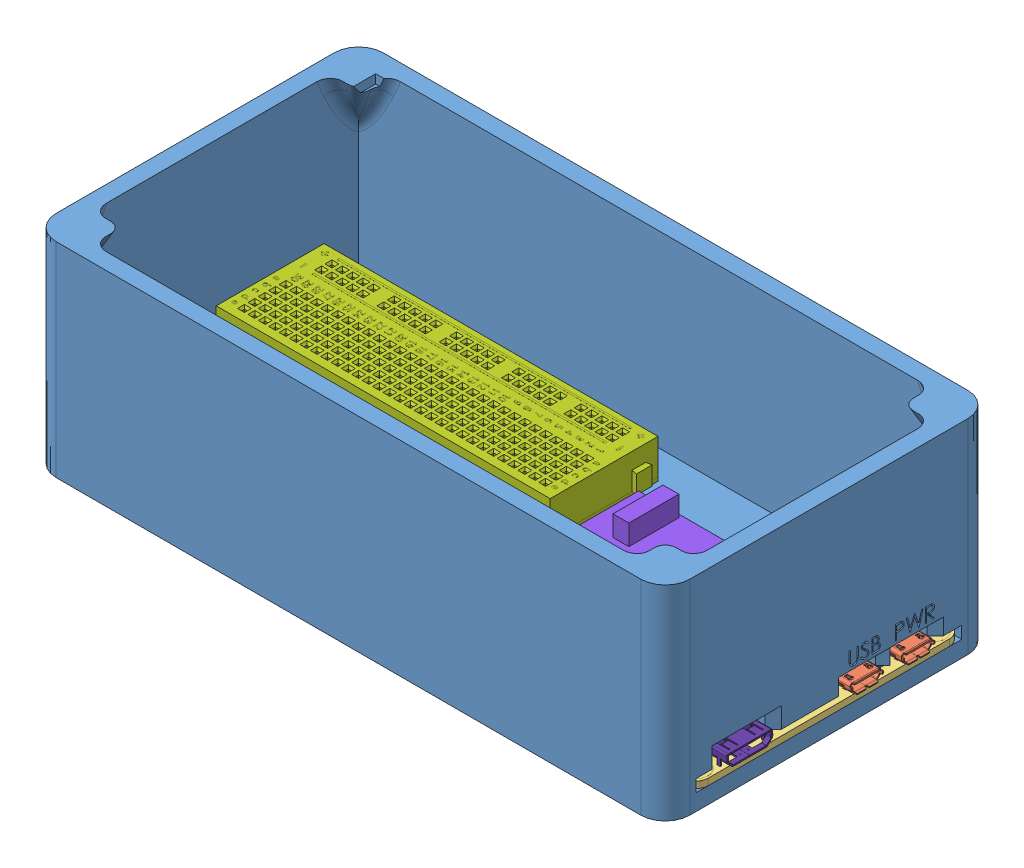
SolidWorks assembly pi, box, configuration Default. Lengths in mm.
Overall size (155.65 50 80).
137 component instances, 26 part files, 12 mates.
Components (placement in the parent):
- pi box-1: pi box [Default] at (-36.1116 -16.0772 12.9936) size (155 50 80)
- Raspberry PI Zero WH-2: Raspberry PI Zero WH [Default] at (41.3884 -12.0772 45.4936) x (0 0 -1) z (0 1 0) size (65 30.65 11.38)
  - micro_usb_connector v17.step-3: micro_usb_connector v17.step [Default] at (41.4 3 1.74) x (0 -1 0) z (0 0 1) size (5.84 7.77 3.4)
    - shield.step-1: shield.step [Default] at origin size (5.84 7.77 3.4)
    - socket_housing.step-1: socket_housing.step [Default] at origin size (4.25 6.85 2.15)
    - socket_plate.step-1: socket_plate.step [Default] at origin size (3.38 6.8 0.31)
    - terminal.step-1: terminal.step [Default] at origin size (3.22 0.35 1.72)
    - terminal.step-2: terminal.step [Default] at (0 -1.3 0) size (3.22 0.35 1.72)
    - terminal.step-3: terminal.step [Default] at (0 -0.65 0) size (3.22 0.35 1.72)
    - terminal.step-4: terminal.step [Default] at (0 0.65 0) size (3.22 0.35 1.72)
    - terminal.step-5: terminal.step [Default] at (0 1.3 0) size (3.22 0.35 1.72)
  - micro_usb_connector v17.step-4: micro_usb_connector v17.step [Default] at (54 3 1.74) x (0 -1 0) z (0 0 1) size (5.84 7.77 3.4)
    - shield.step-1: shield.step [Default] at origin size (5.84 7.77 3.4)
    - socket_housing.step-1: socket_housing.step [Default] at origin size (4.25 6.85 2.15)
    - socket_plate.step-1: socket_plate.step [Default] at origin size (3.38 6.8 0.31)
    - terminal.step-1: terminal.step [Default] at origin size (3.22 0.35 1.72)
    - terminal.step-2: terminal.step [Default] at (0 -1.3 0) size (3.22 0.35 1.72)
    - terminal.step-3: terminal.step [Default] at (0 -0.65 0) size (3.22 0.35 1.72)
    - terminal.step-4: terminal.step [Default] at (0 0.65 0) size (3.22 0.35 1.72)
    - terminal.step-5: terminal.step [Default] at (0 1.3 0) size (3.22 0.35 1.72)
  - Components.step-2: Components.step [Default] at origin size (59.43 22.49 1.8)
    - CAPC-0402-T0.55-BN.step-1: CAPC-0402-T0.55-BN.step [Default] at (33.3698 17.6201 1.6) size (1.05 0.55 0.55)
    - CAPC-0402-T0.55-BN.step-2: CAPC-0402-T0.55-BN.step [Default] at (33.3698 16.6201 1.6) size (1.05 0.55 0.55)
    - CAPC-0402-T0.55-BN.step-3: CAPC-0402-T0.55-BN.step [Default] at (33.3698 15.6201 1.6) size (1.05 0.55 0.55)
    - CAPC-0402-T0.55-BN.step-4: CAPC-0402-T0.55-BN.step [Default] at (33.3698 14.6201 1.6) size (1.05 0.55 0.55)
    - CAPC-0402-T0.55-BN.step-5: CAPC-0402-T0.55-BN.step [Default] at (33.3698 13.6201 1.6) size (1.05 0.55 0.55)
    - CAPC-0402-T0.55-BN.step-6: CAPC-0402-T0.55-BN.step [Default] at (33.3698 12.6201 1.6) size (1.05 0.55 0.55)
    - CAPC-0402-T0.55-BN.step-7: CAPC-0402-T0.55-BN.step [Default] at (33.3698 11.6201 1.6) size (1.05 0.55 0.55)
    - CAPC-0402-T0.55-BN.step-8: CAPC-0402-T0.55-BN.step [Default] at (35.2975 17.3433 1.6) x (0 -1 0) z (0 0 1) size (1.05 0.55 0.55)
    - CAPC-0402-T0.55-BN.step-9: CAPC-0402-T0.55-BN.step [Default] at (35.2975 15.5933 1.6) x (0 -1 0) z (0 0 1) size (1.05 0.55 0.55)
    - CAPC-0402-T0.55-BN.step-10: CAPC-0402-T0.55-BN.step [Default] at (20.7555 5.9273 1.6) x (0 -1 0) z (0 0 1) size (1.05 0.55 0.55)
    - CAPC-0402-T0.55-BN.step-11: CAPC-0402-T0.55-BN.step [Default] at (21.5605 5.9273 1.6) x (0 -1 0) z (0 0 1) size (1.05 0.55 0.55)
    - CAPC-0402-T0.55-BN.step-12: CAPC-0402-T0.55-BN.step [Default] at (22.3655 5.9273 1.6) x (0 -1 0) z (0 0 1) size (1.05 0.55 0.55)
    - CAPC-0402-T0.55-BN.step-13: CAPC-0402-T0.55-BN.step [Default] at (23.1705 5.9273 1.6) x (0 -1 0) z (0 0 1) size (1.05 0.55 0.55)
    - CAPC-0402-T0.55-BN.step-14: CAPC-0402-T0.55-BN.step [Default] at (23.9755 5.9273 1.6) x (0 -1 0) z (0 0 1) size (1.05 0.55 0.55)
    - CAPC-0402-T0.55-BN.step-15: CAPC-0402-T0.55-BN.step [Default] at (24.7805 5.9273 1.6) x (0 -1 0) z (0 0 1) size (1.05 0.55 0.55)
    - CAPC-0402-T0.55-BN.step-16: CAPC-0402-T0.55-BN.step [Default] at (25.5855 5.9273 1.6) x (0 -1 0) z (0 0 1) size (1.05 0.55 0.55)
    - CAPC-0402-T0.55-BN.step-17: CAPC-0402-T0.55-BN.step [Default] at (26.3905 5.9273 1.6) x (0 -1 0) z (0 0 1) size (1.05 0.55 0.55)
    - CAPC-0402-T0.55-BN.step-18: CAPC-0402-T0.55-BN.step [Default] at (27.1955 5.9273 1.6) x (0 -1 0) z (0 0 1) size (1.05 0.55 0.55)
    - CAPC-0402-T0.55-BN.step-19: CAPC-0402-T0.55-BN.step [Default] at (28.0005 5.9273 1.6) x (0 -1 0) z (0 0 1) size (1.05 0.55 0.55)
    - CAPC-0402-T0.55-BN.step-20: CAPC-0402-T0.55-BN.step [Default] at (34.1 10.6 1.6) size (1.05 0.55 0.55)
    - CAPC-0402-T0.55-BN.step-21: CAPC-0402-T0.55-BN.step [Default] at (34.1 9.79 1.6) size (1.05 0.55 0.55)
    - CAPC-0402-T0.55-BN.step-22: CAPC-0402-T0.55-BN.step [Default] at (34.1 8.98 1.6) size (1.05 0.55 0.55)
    - CAPC-0402-T0.55-BN.step-23: CAPC-0402-T0.55-BN.step [Default] at (34.1 8.17 1.6) size (1.05 0.55 0.55)
    - CAPC-0402-T0.55-BN.step-24: CAPC-0402-T0.55-BN.step [Default] at (34.1 7.36 1.6) size (1.05 0.55 0.55)
    - CAPC-0402-T0.55-BN.step-25: CAPC-0402-T0.55-BN.step [Default] at (17.4437 19.1633 1.6) size (1.05 0.55 0.55)
    - CAPC-0402-T0.55-BN.step-26: CAPC-0402-T0.55-BN.step [Default] at (17.4437 18.1633 1.6) size (1.05 0.55 0.55)
    - CAPC-0402-T0.55-BN.step-27: CAPC-0402-T0.55-BN.step [Default] at (17.4437 17.1633 1.6) size (1.05 0.55 0.55)
    - CAPC-0402-T0.55-BN.step-28: CAPC-0402-T0.55-BN.step [Default] at (17.4437 16.1633 1.6) size (1.05 0.55 0.55)
    - CAPC-0402-T0.55-BN.step-29: CAPC-0402-T0.55-BN.step [Default] at (17.4437 15.1633 1.6) size (1.05 0.55 0.55)
    - CAPC-0402-T0.55-BN.step-30: CAPC-0402-T0.55-BN.step [Default] at (17.9697 14.164 1.6) size (1.05 0.55 0.55)
    - CAPC-0402-T0.55-BN.step-31: CAPC-0402-T0.55-BN.step [Default] at (17.9697 13.344 1.6) size (1.05 0.55 0.55)
    - CAPC-0402-T0.55-BN.step-32: CAPC-0402-T0.55-BN.step [Default] at (31.3668 5.5372 1.6) size (1.05 0.55 0.55)
    - CAPC-0402-T0.55-BN.step-33: CAPC-0402-T0.55-BN.step [Default] at (36.2259 10.107 1.6) x (0 -1 0) z (0 0 1) size (1.05 0.55 0.55)
    - CAPC-0402-T0.55-BN.step-34: CAPC-0402-T0.55-BN.step [Default] at (30.8759 20.015 1.6) size (1.05 0.55 0.55)
    - CAPC-0402-T0.55-BN.step-35: CAPC-0402-T0.55-BN.step [Default] at (25.6574 20.7007 1.6) x (0 -1 0) z (0 0 1) size (1.05 0.55 0.55)
    - CAPC-0402-T0.55-BN.step-36: CAPC-0402-T0.55-BN.step [Default] at (24.6574 20.7007 1.6) x (0 -1 0) z (0 0 1) size (1.05 0.55 0.55)
    - CAPC-0402-T0.55-BN.step-37: CAPC-0402-T0.55-BN.step [Default] at (23.6574 20.7007 1.6) x (0 -1 0) z (0 0 1) size (1.05 0.55 0.55)
    - CAPC-0402-T0.55-BN.step-38: CAPC-0402-T0.55-BN.step [Default] at (20.2103 20.6923 1.6) x (0 -1 0) z (0 0 1) size (1.05 0.55 0.55)
    - CAPC-0402-T0.55-BN.step-39: CAPC-0402-T0.55-BN.step [Default] at (39.0204 12.9386 1.6) size (1.05 0.55 0.55)
    - CAPC-0402-T0.55-BN.step-40: CAPC-0402-T0.55-BN.step [Default] at (40.6631 15.6901 1.6) size (1.05 0.55 0.55)
    - CAPC-0402-T0.55-BN.step-41: CAPC-0402-T0.55-BN.step [Default] at (39.3678 16.5618 1.6) size (1.05 0.55 0.55)
    - CAPC-0402-T0.55-BN.step-42: CAPC-0402-T0.55-BN.step [Default] at (42.831 16.9675 1.6) x (0 -1 0) z (0 0 1) size (1.05 0.55 0.55)
    - CAPC-0402-T0.55-BN.step-43: CAPC-0402-T0.55-BN.step [Default] at (41.2678 16.5618 1.6) size (1.05 0.55 0.55)
    - CAPC-0402-T0.55-BN.step-44: CAPC-0402-T0.55-BN.step [Default] at (5.0529 7.1196 1.6) size (1.05 0.55 0.55)
    - CAPC-0402-T0.55-BN.step-45: CAPC-0402-T0.55-BN.step [Default] at (37.9324 22.363 1.6) size (1.05 0.55 0.55)
    - CAPC-0402-T0.55-BN.step-46: CAPC-0402-T0.55-BN.step [Default] at (52.706 14.1667 1.6) size (1.05 0.55 0.55)
    - CAPC-0603-T0.9-BN.step-1: CAPC-0603-T0.9-BN.step [Default] at (1.2622 8.8622 1.6) x (0 -1 0) z (0 0 1) size (1.7 0.9 0.9)
    - CAPC-0402-T0.55-BN.step-47: CAPC-0402-T0.55-BN.step [Default] at (19.3797 6.5002 1.6) size (1.05 0.55 0.55)
    - CAPC-0402-T0.55-BN.step-48: CAPC-0402-T0.55-BN.step [Default] at (19.3316 1.3043 1.6) size (1.05 0.55 0.55)
    - CAPC-0603-T0.9-BN.step-2: CAPC-0603-T0.9-BN.step [Default] at (33.8953 18.8389 1.6) size (1.7 0.9 0.9)
    - INDC-0603.step-1: INDC-0603.step [Default] at (39.8621 18.1224 1.6) size (1.75 0.95 0.95)
    - INDC-0603.step-2: INDC-0603.step [Default] at (39.1295 14.7453 1.6) x (0 -1 0) z (0 0 1) size (1.75 0.95 0.95)
    - INDC-0402.step-1: INDC-0402.step [Default] at (29.426 5.5149 1.6) size (1.05 0.55 0.55)
    - INDC-0402.step-2: INDC-0402.step [Default] at (41.7855 10.5602 1.6) size (1.05 0.55 0.55)
    - INDC-0402.step-3: INDC-0402.step [Default] at (41.7855 9.7502 1.6) size (1.05 0.55 0.55)
    - INDC-0402.step-4: INDC-0402.step [Default] at (46.2071 10.726 1.6) size (1.05 0.55 0.55)
    - INDC-0402.step-5: INDC-0402.step [Default] at (18.9188 8.3162 1.6) size (1.05 0.55 0.55)
    - INDC-0402.step-6: INDC-0402.step [Default] at (16.9188 8.3162 1.6) size (1.05 0.55 0.55)
    - CAPC-0805-T0.95-BN.step-1: CAPC-0805-T0.95-BN.step [Default] at (27.8612 20.5927 1.6) size (2.1 1.35 0.95)
    - CAPC-0805-T0.95-BN.step-2: CAPC-0805-T0.95-BN.step [Default] at (27.8612 22.8427 1.6) size (2.1 1.35 0.95)
    - CAPC-0805-T0.95-BN.step-3: CAPC-0805-T0.95-BN.step [Default] at (51.017 11.9186 1.6) x (0 -1 0) z (0 0 1) size (2.1 1.35 0.95)
    - CAPC-0805-T0.95-BN.step-4: CAPC-0805-T0.95-BN.step [Default] at (52.817 11.9186 1.6) x (0 -1 0) z (0 0 1) size (2.1 1.35 0.95)
    - CAPC-0805-T0.95-BN.step-5: CAPC-0805-T0.95-BN.step [Default] at (57.6691 12.6645 1.6) x (0 -1 0) z (0 0 1) size (2.1 1.35 0.95)
    - CAPC-0805-T0.95-BN.step-6: CAPC-0805-T0.95-BN.step [Default] at (59.5691 12.6645 1.6) x (0 -1 0) z (0 0 1) size (2.1 1.35 0.95)
    - CAPC-1206-T1.4-BN.step-1: CAPC-1206-T1.4-BN.step [Default] at (55.8544 7.8017 1.6) x (0 -1 0) z (0 0 1) size (3.35 1.75 1.4)
    - CAPC-0805-T0.95-BN.step-7: CAPC-0805-T0.95-BN.step [Default] at (47.3323 2.998 1.6) size (2.1 1.35 0.95)
    - RESC-0402.step-1: RESC-0402.step [Default] at (35.3052 13.8988 1.6) x (0 -1 0) z (0 0 1) size (1.05 0.55 0.4)
    - RESC-0402.step-2: RESC-0402.step [Default] at (35.3052 12.2988 1.6) x (0 -1 0) z (0 0 1) size (1.05 0.55 0.4)
    - RESC-0402.step-3: RESC-0402.step [Default] at (35.3713 10.1216 1.6) x (0 -1 0) z (0 0 1) size (1.05 0.55 0.4)
    - RESC-0402.step-4: RESC-0402.step [Default] at (14.6084 13.087 1.6) x (0 1 0) z (0 0 1) size (1.05 0.55 0.4)
    - RESC-0402.step-5: RESC-0402.step [Default] at (13.9844 22.5264 1.6) x (0 -1 0) z (0 0 1) size (1.05 0.55 0.4)
    - RESC-0402.step-6: RESC-0402.step [Default] at (15.3844 22.5264 1.6) x (0 -1 0) z (0 0 1) size (1.05 0.55 0.4)
    - RESC-0402.step-7: RESC-0402.step [Default] at (4.6621 10.2008 1.6) size (1.05 0.55 0.4)
    - RESC-0402.step-8: RESC-0402.step [Default] at (58.3516 9.0224 1.6) x (0 1 0) z (0 0 1) size (1.05 0.55 0.4)
    - RESC-0402.step-9: RESC-0402.step [Default] at (59.1516 9.0224 1.6) x (0 1 0) z (0 0 1) size (1.05 0.55 0.4)
    - RESC-0402.step-10: RESC-0402.step [Default] at (59.9516 9.0224 1.6) x (0 1 0) z (0 0 1) size (1.05 0.55 0.4)
    - RESC-0402.step-11: RESC-0402.step [Default] at (36.9521 21.579 1.6) size (1.05 0.55 0.4)
    - CAPC-0402-T0.55-BN.step-49: CAPC-0402-T0.55-BN.step [Default] at (30.8759 21.315 1.6) size (1.05 0.55 0.55)
    - RESC-0402.step-12: RESC-0402.step [Default] at (47.4882 18.8168 1.6) x (0.707107 0.707107 0) z (0 0 1) size (1.05 0.55 0.4)
    - RESC-0402.step-13: RESC-0402.step [Default] at (52.3627 20.1006 1.6) x (0 1 0) z (0 0 1) size (1.05 0.55 0.4)
    - RESC-0402.step-14: RESC-0402.step [Default] at (53.0236 15.6867 1.6) size (1.05 0.55 0.4)
    - SRN4018.step-1: SRN4018.step [Default] at (57.7919 17.1897 1.6) size (4.2 4.2 1.8)
    - Components-0.step-1: Components-0.step [Default] at origin size (12.01 12.01 1)
    - Components-1.step-1: Components-1.step [Default] at origin size (4.88 2.9 0.6)
  - Mini HDMI.step-2: Mini HDMI.step [Default] at (12.5 5.85 3.1) x (0 -1 0) z (0 0 1) size (7.9 11.25 5.45)
    - Housing.step-1: Housing.step [Default] at origin size (5.5 11.25 2.9)
    - Shielding.step-1: Shielding.step [Default] at (2.875 0 0.82) x (0 1 0) z (0 0 1) size (11.21 7.6 5.45)
    - Housing2.step-1: Housing2.step [Default] at (-0.075 0 -0.65) x (0 -1 0) z (0 0 1) size (8.25 0.75 1.6)
    - Pin1.step-1: Pin1.step [Default] at (2.1 -3.6 0.3) size (5.9 0.15 1.8)
    - Pin1.step-2: Pin1.step [Default] at (2.1 -2.8 0.3) size (5.9 0.15 1.8)
    - Pin1.step-3: Pin1.step [Default] at (2.1 -2.4 0.3) size (5.9 0.15 1.8)
    - Pin1.step-4: Pin1.step [Default] at (2.1 -2 0.3) size (5.9 0.15 1.8)
    - Pin1.step-5: Pin1.step [Default] at (2.1 -1.6 0.3) size (5.9 0.15 1.8)
    - Pin1.step-6: Pin1.step [Default] at (2.1 -1.2 0.3) size (5.9 0.15 1.8)
    - Pin1.step-7: Pin1.step [Default] at (2.1 -0.8 0.3) size (5.9 0.15 1.8)
    - Pin1.step-8: Pin1.step [Default] at (2.1 -0.4 0.3) size (5.9 0.15 1.8)
    - Pin1.step-9: Pin1.step [Default] at (2.1 0 0.3) size (5.9 0.15 1.8)
    - Pin1.step-10: Pin1.step [Default] at (2.1 0.4 0.3) size (5.9 0.15 1.8)
    - Pin1.step-11: Pin1.step [Default] at (2.1 0.8 0.3) size (5.9 0.15 1.8)
    - Pin1.step-12: Pin1.step [Default] at (2.1 1.2 0.3) size (5.9 0.15 1.8)
    - Pin1.step-13: Pin1.step [Default] at (2.1 1.6 0.3) size (5.9 0.15 1.8)
    - Pin1.step-14: Pin1.step [Default] at (2.1 2 0.3) size (5.9 0.15 1.8)
    - Pin1.step-15: Pin1.step [Default] at (2.1 2.4 0.3) size (5.9 0.15 1.8)
    - Pin1.step-16: Pin1.step [Default] at (2.1 2.8 0.3) size (5.9 0.15 1.8)
    - Pin1.step-17: Pin1.step [Default] at (2.1 3.2 0.3) size (5.9 0.15 1.8)
    - Pin1.step-18: Pin1.step [Default] at (2.1 3.6 0.3) size (5.9 0.15 1.8)
    - Pin2.step-1: Pin2.step [Default] at (1.7983 -3.2 0.3) size (5.3 0.15 1.8)
  - Board.step-2: Board.step [Default] at origin size (65 30 1.62)
  - HDRV40W64P254_2X20_5080X508X838B.step-2: HDRV40W64P254_2X20_5080X508X838B.step [Default] at (8.37 27.77 1.6) size (50.8 5.08 11.38)
  - Micro SD slot.step-2: Micro SD slot.step [Default] at (7.3191 16.9624 1.57) x (0 -1 0) z (-1 0 0) size (11.95 1.45 11.4)
- magnet-1: magnet [Default] at (-107.6116 31.5228 -21.0064) size (6 2 6)
- magnet-2: magnet [Default] at (35.3884 31.5228 -21.0064) x (0.982082 0 -0.188455) z (0.188455 0 0.982082) size (6 2 6)
- magnet-4: magnet [Default] at (-107.6116 31.5228 46.9936) x (0.918365 0 -0.395734) z (0.395734 0 0.918365) size (6 2 6)
- magnet-6: magnet [Default] at (35.3884 31.5228 46.9936) x (0.8 0 -0.6) z (0.6 0 0.8) size (6 2 6)
- HalfBreadboard-1: HalfBreadboard [Default] at (-68.7716 -5.5063 54.7506) x (0 0 1) z (-1 0 0) size (56.08 9.51 83.01)
- stepper_driver-1: stepper_driver [Default] at (-7.5002 -8.8272 9.3071) size (34.66 6.5 32)
Mates (geometry in assembly coordinates):
- Coincident8: coincident: plane of pi box-1 through (-36.1116 -12.0772 12.9936) normal (0 1 0); plane of Raspberry PI Zero WH-1/Board.step-1 through (26.3884 -12.0772 16.9226) normal (0 -1 0)
- Coincident2: coincident anti-aligned: plane of pi box-1 through (-107.6116 31.5228 -21.0064) normal (0 1 0); plane of magnet-1 through (-107.6116 31.5228 -21.0064) normal (0 -1 0)
- Concentric1: concentric anti-aligned: cylinder of pi box-1 through (-107.6116 31.5228 -21.0064) axis (0 1 0) radius 3.15; cylinder of magnet-1 through (-107.6116 33.5228 -21.0064) axis (0 -1 0) radius 3
- Coincident3: coincident anti-aligned: plane of pi box-1 through (35.3884 31.5228 -21.0064) normal (0 1 0); plane of magnet-2 through (35.3884 31.5228 -21.0064) normal (0 -1 0)
- Concentric2: concentric anti-aligned: cylinder of pi box-1 through (35.3884 31.5228 -21.0064) axis (0 1 0) radius 3.15; cylinder of magnet-2 through (35.3884 33.5228 -21.0064) axis (0 -1 0) radius 3
- Coincident4: coincident anti-aligned: plane of pi box-1 through (-107.6116 31.5228 46.9936) normal (0 1 0); plane of magnet-4 through (-107.6116 31.5228 46.9936) normal (0 -1 0)
- Concentric3: concentric anti-aligned: cylinder of pi box-1 through (-107.6116 31.5228 46.9936) axis (0 1 0) radius 3.15; cylinder of magnet-4 through (-107.6116 33.5228 46.9936) axis (0 -1 0) radius 3
- Coincident5: coincident anti-aligned: plane of pi box-1 through (35.3884 31.5228 46.9936) normal (0 1 0); plane of magnet-6 through (35.3884 31.5228 46.9936) normal (0 -1 0)
- Concentric4: concentric anti-aligned: cylinder of pi box-1 through (35.3884 31.5228 46.9936) axis (0 1 0) radius 3.15; cylinder of magnet-6 through (35.3884 33.5228 46.9936) axis (0 -1 0) radius 3
- Coincident6: coincident anti-aligned: plane of pi box-1 through (-109.6116 33.9228 52.9936) normal (1 0 0); plane of HalfBreadboard-1 through (-109.6116 -1.2563 40.2156) normal (-1 0 0)
- Coincident7: coincident: plane of pi box-1 through (41.3884 33.9228 52.9936) normal (1 0 0); line of Raspberry PI Zero WH-1/Board.step-1 through (41.3884 -10.4772 46.4226) axis (0 0 -1)
- Concentric5: concentric aligned: cylinder of pi box-1 through (14.8884 -16.0772 -16.0064) axis (0 1 0) radius 1.25; cylinder of Raspberry PI Zero WH-1/Board.step-1 through (14.8884 -12.0772 -16.0064) axis (0 1 0) radius 1.25
